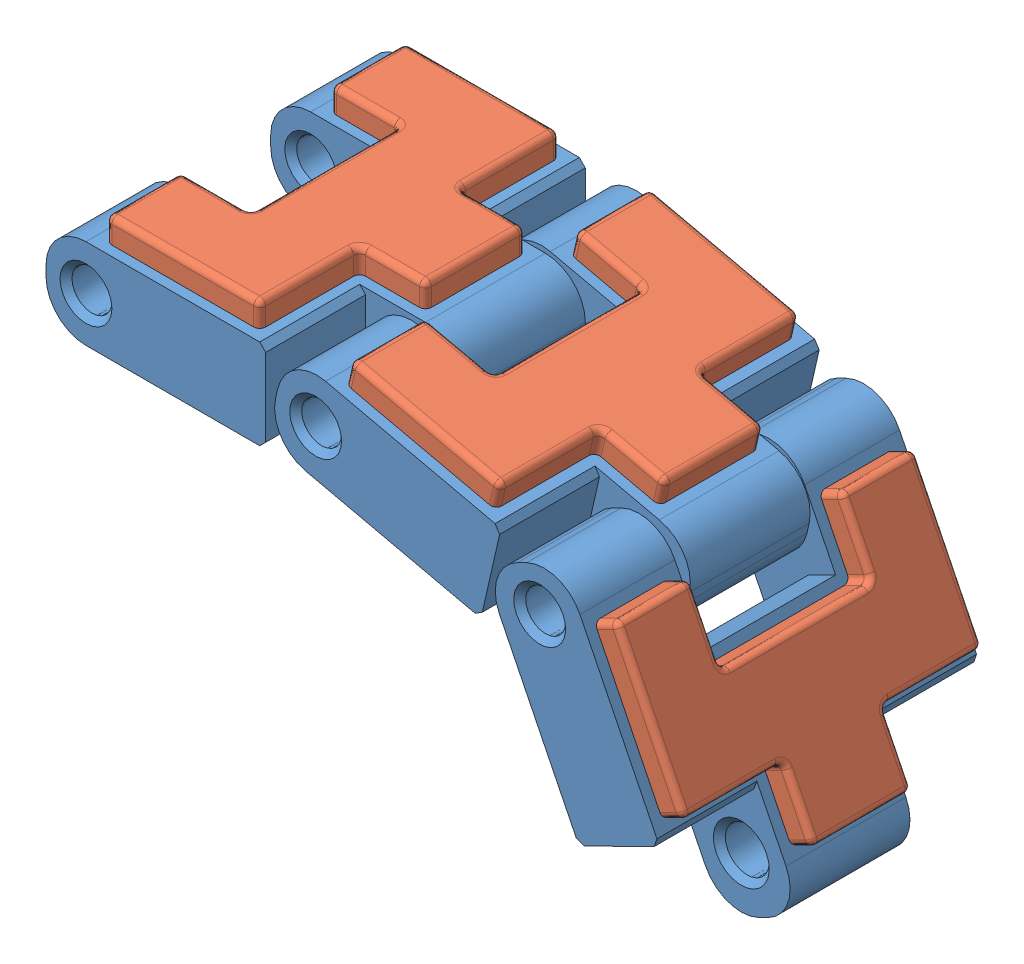
SolidWorks assembly bg_PipeMouse_SimulationGummiKette, configuration Standard. Lengths in mm.
Overall size (34.01 19.9 16).
9 component instances, 2 part files, 4 mates.
Components (placement in the parent):
- bg_PipeMouse_KettenGliedGummi-1: bg_PipeMouse_KettenGliedGummi [Standard] at (-1.2555 -0.1049 0) size (16 5.7 16)
  - pipemouse_Kettenglied-1: pipemouse_Kettenglied [MoosV] at (-9.6091 -2.9927 16) size (16 4.5 16)
  - pipemouse_GummiPlatte-1: pipemouse_GummiPlatte [Standard] at (-3.6091 2.7073 16) x (1 0 0) z (0 -1 0) size (11 15 2)
- bg_PipeMouse_KettenGliedGummi-2: bg_PipeMouse_KettenGliedGummi [Standard] at (10.2202 -1.8074 0) x (0.975199 -0.221329 0) z (0 0 1) size (16 5.7 16)
  - pipemouse_Kettenglied-1: pipemouse_Kettenglied [MoosV] at (-9.6091 -2.9927 16) size (16 4.5 16)
  - pipemouse_GummiPlatte-1: pipemouse_GummiPlatte [Standard] at (-3.6091 2.7073 16) x (1 0 0) z (0 -1 0) size (11 15 2)
- bg_PipeMouse_KettenGliedGummi-3: bg_PipeMouse_KettenGliedGummi [Standard] at (17.887 -9.8855 0) x (0.443024 -0.89651 0) z (0 0 1) size (16 5.7 16)
  - pipemouse_Kettenglied-1: pipemouse_Kettenglied [MoosV] at (-9.6091 -2.9927 16) size (16 4.5 16)
  - pipemouse_GummiPlatte-1: pipemouse_GummiPlatte [Standard] at (-3.6091 2.7073 16) x (1 0 0) z (0 -1 0) size (11 15 2)
Mates (geometry in assembly coordinates):
- Breite1: width anti-aligned: plane of bg_PipeMouse_KettenGliedGummi-2/pipemouse_Kettenglied-1 through (6.5466 0.572 12.75) normal (0 0 1); plane of bg_PipeMouse_KettenGliedGummi-1/pipemouse_Kettenglied-1 through (6.5466 0.572 19.25) normal (0 0 -1); plane of bg_PipeMouse_KettenGliedGummi-2/pipemouse_Kettenglied-1 through (0.1354 1.4024 13) normal (0 0 -1); plane of bg_PipeMouse_KettenGliedGummi-1/pipemouse_Kettenglied-1 through (0.1354 1.4024 19) normal (0 0 1)
- Konzentrisch1: concentric aligned: cylinder of bg_PipeMouse_KettenGliedGummi-1/pipemouse_Kettenglied-1 through (2.6354 -0.8476 8) axis (0 0 1) radius 1.1; cylinder of bg_PipeMouse_KettenGliedGummi-2/pipemouse_Kettenglied-1 through (2.6354 -0.8476 8) axis (0 0 1) radius 1
- Breite2: width anti-aligned: plane of bg_PipeMouse_KettenGliedGummi-3/pipemouse_Kettenglied-1 through (17.4179 -5.5338 12.75) normal (0 0 1); plane of bg_PipeMouse_KettenGliedGummi-2/pipemouse_Kettenglied-1 through (17.4179 -5.5338 19.25) normal (0 0 -1); plane of bg_PipeMouse_KettenGliedGummi-3/pipemouse_Kettenglied-1 through (11.9101 -0.6453 13) normal (0 0 -1); plane of bg_PipeMouse_KettenGliedGummi-2/pipemouse_Kettenglied-1 through (11.9101 -0.6453 19) normal (0 0 1)
- Konzentrisch2: concentric aligned: cylinder of bg_PipeMouse_KettenGliedGummi-2/pipemouse_Kettenglied-1 through (13.8502 -3.3928 8) axis (0 0 1) radius 1.1; cylinder of bg_PipeMouse_KettenGliedGummi-3/pipemouse_Kettenglied-1 through (13.8502 -3.3928 8) axis (0 0 1) radius 1
